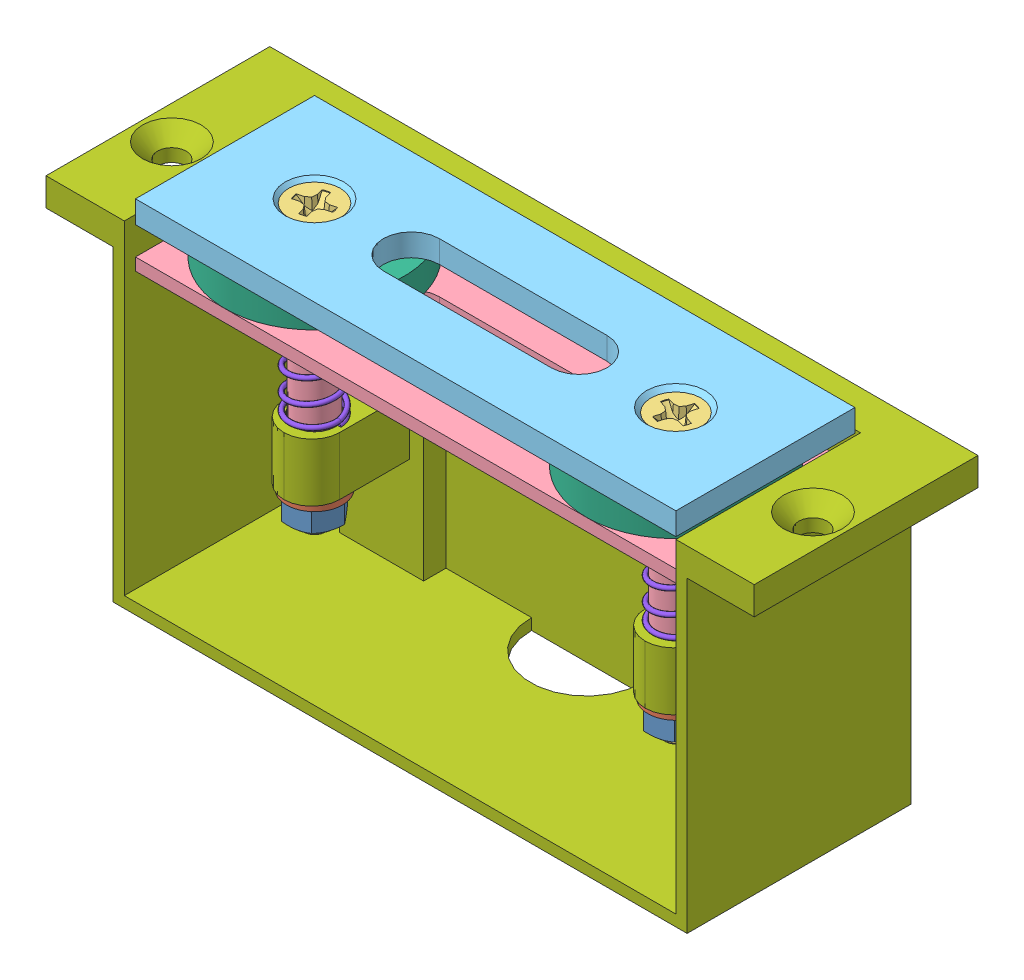
SolidWorks assembly Contact_box, configuration Défaut. Lengths in mm.
Overall size (126.6 63.43 45.29).
13 component instances, 8 part files, 30 mates.
Components (placement in the parent):
- 90592A095_STEEL HEX NUT-1: 90592A095_STEEL HEX NUT [90592A095] at (42.366 -37.9 -16) x (-0.939842 0 -0.341611) z (-0.341611 0 0.939842) size (8 4.7 9.24)
- 90965A160_TYPE 316 STAINLESS STEEL FLAT WASHER-1: 90965A160_TYPE 316 STAINLESS STEEL FLAT WASHER [90965A160] at (42.366 -34.8 -16) x (0.926814 0 0.37552) z (0 -1 0) size (10 10 1.1)
- 92010A346_METRIC 18-8 SS FLAT HEAD PHIL MACHINE SCREW-1: 92010A346_METRIC 18-8 SS FLAT HEAD PHIL MACHINE SCREW [92010A346] at (42.366 5.8508 -16) x (-0.964493 0 0.264109) z (0 1 0) size (9.2 9.2 50.9)
- Slider_double-2: Slider_double [Défaut] at (73.9948 0 -18.2599) x (1 0 0) z (0 -1 0) size (96.6 32 34.8)
- 90592A095_STEEL HEX NUT-2: 90592A095_STEEL HEX NUT [90592A095] at (106.966 -37.9 -16) x (-0.227533 0 -0.97377) z (-0.97377 0 0.227533) size (8 4.7 9.24)
- 90965A160_TYPE 316 STAINLESS STEEL FLAT WASHER-2: 90965A160_TYPE 316 STAINLESS STEEL FLAT WASHER [90965A160] at (106.966 -35.9 -16) x (0.854168 0 -0.519996) z (0 1 0) size (10 10 1.1)
- 92010A346_METRIC 18-8 SS FLAT HEAD PHIL MACHINE SCREW-2: 92010A346_METRIC 18-8 SS FLAT HEAD PHIL MACHINE SCREW [92010A346] at (106.966 5.7343 -16) x (-0.958526 0 -0.285004) z (0 1 0) size (9.2 9.2 50.9)
- Front_piece-1: Front_piece [Défaut] at (46.2484 5 -15.3287) x (1 0 0) z (0 1 0) size (96.6 32 4)
- Magnet-1: Magnet [Défaut] at (106.9751 0 -52.0795) x (-0.575378 0 -0.817888) z (0 1 0) size (32 32 5)
- Magnet-2: Magnet [Défaut] at (64.3425 0 -44.6141) x (0.041611 0 -0.999134) z (0 1 0) size (32 32 5)
- Base_of_box-1: Base_of_box [Défaut] at (40.8338 5.5749 -18.1867) x (1 0 0) z (0 -1 0) size (126.6 40 60)
- 9434K730_MUSIC-WIRE STEEL COMPRESSION SPRINGS-1: 9434K730_MUSIC-WIRE STEEL COMPRESSION SPRINGS [9434K73] at (42.1198 -24.425 -16.187) x (0.998669 0 -0.051587) z (0.051587 0 0.998669) size (9.43 22.63 9.54)
- 9434K730_MUSIC-WIRE STEEL COMPRESSION SPRINGS-2: 9434K730_MUSIC-WIRE STEEL COMPRESSION SPRINGS [9434K73] at (107.1898 -24.425 -16.213) x (0.99824 0 -0.05931) z (0.05931 0 0.99824) size (9.43 22.63 9.54)
Mates (geometry in assembly coordinates):
- Coincident22: coincident anti-aligned: line of 90592A095_STEEL HEX NUT-1 through (42.366 -37.1021 -16) axis (0 1 0); line of 92010A346_METRIC 18-8 SS FLAT HEAD PHIL MACHINE SCREW-1 through (42.366 8.3508 -16) axis (0 -1 0)
- Screw4: screw = 0.8 mm aligned: cylinder of 90592A095_STEEL HEX NUT-1 through (42.366 -39.9 -16) axis (0 1 0) radius 2.5; cylinder of 92010A346_METRIC 18-8 SS FLAT HEAD PHIL MACHINE SCREW-1 through (42.366 8.3508 -16) axis (0 1 0) radius 2.5
- Coincident26: coincident anti-aligned: line of 92010A346_METRIC 18-8 SS FLAT HEAD PHIL MACHINE SCREW-1 through (42.366 8.3508 -16) axis (0 -1 0); line of Slider_double-2 through (42.366 -34.8 -16) axis (0 1 0)
- Coincident27: coincident aligned: plane of Slider_double-2 through (73.9948 0 -18.2599) normal (0 1 0); plane of assembly through (0 0 0) normal (0 1 0)
- Coincident28: coincident aligned: plane of Slider_double-2 through (26.366 -2.2 0) normal (0 0 1); plane of assembly through (0 0 0) normal (0 0 1)
- Coincident30: coincident anti-aligned: plane of 90965A160_TYPE 316 STAINLESS STEEL FLAT WASHER-1 through (42.366 -35.9 -16) normal (0 -1 0); plane of 90592A095_STEEL HEX NUT-1 through (46.9142 -35.9 -16.804) normal (0 1 0)
- Coincident31: coincident aligned: line of 90592A095_STEEL HEX NUT-1 through (42.366 -39.9 -16) axis (0 1 0); line of 90965A160_TYPE 316 STAINLESS STEEL FLAT WASHER-1 through (42.366 -35.9 -16) axis (0 1 0)
- Coincident37: coincident anti-aligned: line of Slider_double-2 through (106.966 -34.8 -16) axis (0 1 0); line of 92010A346_METRIC 18-8 SS FLAT HEAD PHIL MACHINE SCREW-2 through (106.966 8.2343 -16) axis (0 -1 0)
- Coincident38: coincident anti-aligned: line of 90592A095_STEEL HEX NUT-2 through (106.966 -37.1021 -16) axis (0 1 0); line of 92010A346_METRIC 18-8 SS FLAT HEAD PHIL MACHINE SCREW-2 through (106.966 8.2343 -16) axis (0 -1 0)
- Screw7: screw = 0.8 mm aligned: cylinder of 90592A095_STEEL HEX NUT-2 through (106.966 -39.9 -16) axis (0 1 0) radius 2.5; cylinder of 92010A346_METRIC 18-8 SS FLAT HEAD PHIL MACHINE SCREW-2 through (106.966 -41.7657 -16) axis (0 1 0) radius 1.9588
- Coincident39: coincident anti-aligned: plane of 90592A095_STEEL HEX NUT-2 through (110.1249 -35.9 -12.6304) normal (0 1 0); plane of 90965A160_TYPE 316 STAINLESS STEEL FLAT WASHER-2 through (106.966 -35.9 -16) normal (0 -1 0)
- Coincident40: coincident aligned: line of 90965A160_TYPE 316 STAINLESS STEEL FLAT WASHER-2 through (106.966 -34.8 -16) axis (0 -1 0); line of 92010A346_METRIC 18-8 SS FLAT HEAD PHIL MACHINE SCREW-2 through (106.966 8.2343 -16) axis (0 -1 0)
- Coincident43: coincident anti-aligned: line of Slider_double-2 through (122.966 -2.2 -32) axis (0 1 0); line of Front_piece-1 through (122.966 9 -32) axis (0 -1 0)
- Coincident45: coincident aligned: line of 92010A346_METRIC 18-8 SS FLAT HEAD PHIL MACHINE SCREW-2 through (106.966 8.2343 -16) axis (0 -1 0); line of Magnet-1 through (106.966 5 -16) axis (0 -1 0)
- Coincident47: coincident aligned: line of 92010A346_METRIC 18-8 SS FLAT HEAD PHIL MACHINE SCREW-1 through (42.366 8.3508 -16) axis (0 -1 0); line of Magnet-2 through (42.366 5 -16) axis (0 -1 0)
- Coïncidente3: coincident anti-aligned: line of 92010A346_METRIC 18-8 SS FLAT HEAD PHIL MACHINE SCREW-2 through (106.966 8.2343 -16) axis (0 -1 0); line of Base_of_box-1 through (106.966 -34.805 -16) axis (0 1 0)
- Coïncidente8: coincident aligned: line of 92010A346_METRIC 18-8 SS FLAT HEAD PHIL MACHINE SCREW-1 through (42.366 8.3508 -16) axis (0 -1 0); line of Front_piece-1 through (42.366 9 -16) axis (0 -1 0)
- Coïncidente9: coincident aligned: plane of Slider_double-2 through (73.9948 0 -18.2599) normal (0 1 0); circle of Magnet-2
- Coïncidente10: coincident anti-aligned: plane of Slider_double-2 through (73.9948 0 -18.2599) normal (0 1 0); plane of Magnet-1 through (106.966 0 -16) normal (0 -1 0)
- Coïncidente11: coincident anti-aligned: plane of Front_piece-1 through (46.2484 5 -15.3287) normal (0 -1 0); plane of Magnet-1 through (106.966 5 -16) normal (0 1 0)
- Coïncidente12: coincident anti-aligned: plane of Slider_double-2 through (73.9948 -2.2 -18.2599) normal (0 -1 0); plane of 9434K730_MUSIC-WIRE STEEL COMPRESSION SPRINGS-1 through (37.318 -2.2 -20.5171) normal (0 1 0)
- Coïncidente13: coincident anti-aligned: plane of Slider_double-2 through (73.9948 -2.2 -18.2599) normal (0 -1 0); plane of 9434K730_MUSIC-WIRE STEEL COMPRESSION SPRINGS-2 through (102.3547 -2.2 -20.5058) normal (0 1 0)
- Coïncidente14: coincident anti-aligned: plane of Slider_double-2 through (73.9948 -2.2 -18.2599) normal (0 -1 0); plane of 9434K730_MUSIC-WIRE STEEL COMPRESSION SPRINGS-2 through (102.3547 -2.2 -20.5058) normal (0 1 0)
- Tangent1: tangent anti-aligned: cylinder of Slider_double-2 through (106.966 -34.8 -16) axis (0 1 0) radius 3.45; face of 9434K730_MUSIC-WIRE STEEL COMPRESSION SPRINGS-2
- Tangent2: tangent anti-aligned: cylinder of Slider_double-2 through (42.366 -34.8 -16) axis (0 1 0) radius 3.45; edge_curve of 9434K730_MUSIC-WIRE STEEL COMPRESSION SPRINGS-1
- Coïncidente16: coincident anti-aligned: plane of 90965A160_TYPE 316 STAINLESS STEEL FLAT WASHER-1 through (42.366 -34.8 -16) normal (0 1 0); plane of Slider_double-2 through (42.366 -34.8 -16) normal (0 -1 0)
- Coïncidente17: coincident anti-aligned: plane of Slider_double-2 through (106.966 -34.8 -16) normal (0 -1 0); plane of 90965A160_TYPE 316 STAINLESS STEEL FLAT WASHER-2 through (106.966 -34.8 -16) normal (0 1 0)
- Coïncidente18: coincident anti-aligned: line of 92010A346_METRIC 18-8 SS FLAT HEAD PHIL MACHINE SCREW-1 through (42.366 8.3508 -16) axis (0 -1 0); line of Base_of_box-1 through (42.366 -34.805 -16) axis (0 1 0)
- Coïncidente19: coincident anti-aligned: plane of Base_of_box-1 through (101.966 -24.425 -10.5) normal (0 1 0); plane of 9434K730_MUSIC-WIRE STEEL COMPRESSION SPRINGS-2 through (102.3547 -24.425 -20.5058) normal (0 -1 0)
- Coïncidente20: coincident anti-aligned: line of Slider_double-2 through (74.666 0 -16) axis (0 -1 0); line of Front_piece-1 through (74.666 5 -16) axis (0 1 0)
